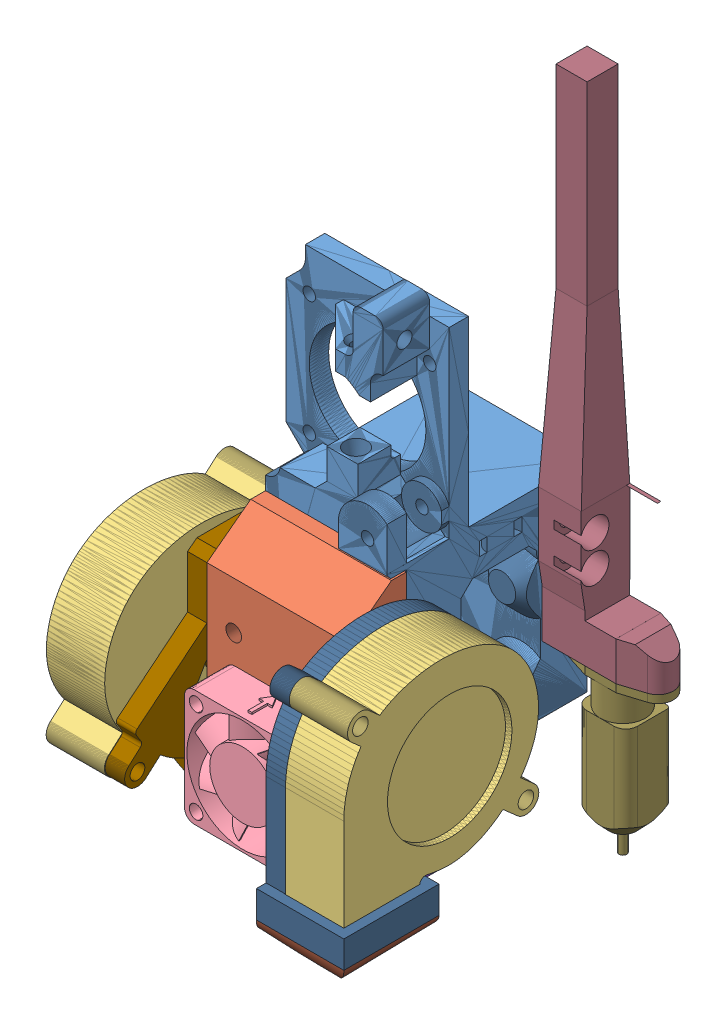
SolidWorks assembly Extrusor, configuration Predeterminado. Lengths in mm.
Overall size (87.36 190.4 95.75).
15 component instances, 13 part files, 34 mates.
Components (placement in the parent):
- mount_motor-1: mount_motor [Predeterminado] at origin size (42 104.07 51.5)
- mount_motor_b_featureworks-2: mount_motor_b_featureworks [Predeterminado] at (5.75 -10 32.6) size (36.25 60 29)
- BlowerFan50-1: BlowerFan50 [Predeterminado] at (-14.25 -3.2581 32.7961) x (0 0 1) z (-1 0 0) size (50.18 49.25 15)
- BlowerFan50-2: BlowerFan50 [Predeterminado] at (62 -3.2581 82.6073) x (0 0 -1) z (1 0 0) size (50.18 49.25 15)
- 30mm Fan-1: 30mm Fan [Predeterminado] at (25.4698 7.0502 72.1) x (1 0 0) z (0 0 -1) size (30 30.5 10.5)
- ED3V6-1: ED3V6 [Predeterminado] at (25.5254 -6.75 42.9799) x (-1 0 0) z (0 0 -1) size (26.65 63.25 22.3)
  - HEATSINK-1: HEATSINK [Predeterminado] at origin size (22.3 42.7 22.3)
  - NOZZLE 0.4-1: NOZZLE 0.4 [Predeterminado] at (0 -18.55 0) x (0.999537 0 -0.030412) z (0.030412 0 0.999537) size (8.08 12.5 7)
  - HEATBRICK-1: HEATBRICK [Predeterminado] at (0 -7.6 0) x (0.965851 0 -0.259098) z (0.259098 0 0.965851) size (7 21.9 7)
  - HEATERBLOCK-1: HEATERBLOCK [Predeterminado] at (-5.5 -15.1 0) size (20 11.5 16)
- FanAdapterWide-1: FanAdapterWide [Predeterminado] at (0.75 -3.2581 32.7961) x (0 0 -1) z (1 0 0) size (52.78 90.63 58.11)
- FanAdapterNarrow^Extrusor-1: FanAdapterNarrow^Extrusor [Predeterminado] at (42 -10 32.6) x (0 0 -1) z (1 0 0) size (63.31 92.39 40.57)
- FanAdapterNarrowTube-1: FanAdapterNarrowTube [Default] at origin size (42.1 18.18 31.65)
- BL-touch-1: BL-touch [Predeterminado] at (57 17.1 5.7838) x (-1 0 0) z (0 1 0) size (26 11.57 42.4)
- soporteBL-1: soporteBL [Predeterminado] at (42 -1.9435 -44.0657) x (0 0 -1) z (1 0 0) size (12.51 126.9 28)
Mates (geometry in assembly coordinates):
- Distancia1: distance = 0 mm: line of mount_motor-1 through (5.75 23 46.5) axis (0 1 0); line of mount_motor_b_featureworks-2 through (5.75 50 46.5) axis (0 -1 0)
- Distancia2: distance = 0 mm: line of mount_motor_b_featureworks-2 through (42 23 46.5) axis (0 0 -1); line of mount_motor-1 through (42 23 46.5) axis (0 0 -1)
- Coincidente3: coincident: point of mount_motor_b_featureworks-2; point of 30mm Fan-1
- Distancia4: distance = 0.2 mm anti-aligned: plane of ED3V6-1/HEATSINK-1 through (17.5254 35.95 42.9799) normal (0 1 0); plane of mount_motor-1 through (0 36.15 0) normal (0 -1 0)
- EnPosición1: in place: plane of ? through (-9.2109 -10.1962 32.7961) normal (0 -1 0); plane of ? through (0 -10.1962 0) normal (0 -1 0); moOrthogonalPlaneRef_w of ? through (-9.2109 -10.1962 32.7961) normal (0 -1 0); unknown of ?; plane of ? through (-9.2109 -10.1962 32.7961) normal (0 -1 0); line of ? through (-55 0 -10.1962) axis (0 -1 0); plane of ? through (-9.2109 -10.1962 32.7961) normal (0 -1 0); unknown of ?
- Coincidente13: coincident aligned: plane of BlowerFan50-1; plane of ?
- Coincidente14: coincident aligned: moOrthogonalPlaneRef_w of BlowerFan50-1 through (-9.2109 -10.1962 32.7961) normal (1 0 0); plane of ?
- Coincidente15: coincident anti-aligned: moOrthogonalPlaneRef_w of BlowerFan50-1 through (-9.2109 -10.1962 32.7961) normal (0 0 1); plane of ?
- EnPosición2: in place: plane of ? through (-9.2109 -10.1962 32.7961) normal (0 -1 0); plane of ? through (0 -10.1962 0) normal (0 -1 0); plane of ? through (-9.2109 -10.1962 32.7961) normal (0 -1 0); unknown of ?; plane of ? through (-9.2109 -10.1962 32.7961) normal (0 -1 0); line of ? through (-55 0 -10.1962) axis (0 -1 0); plane of ? through (-9.2109 -10.1962 32.7961) normal (0 -1 0); unknown of ?
- Coincidente16: coincident aligned: plane of BlowerFan50-1; plane of ?
- Coincidente17: coincident aligned: moOrthogonalPlaneRef_w of BlowerFan50-1 through (-9.2109 -10.1962 32.7961) normal (1 0 0); plane of ?
- Coincidente18: coincident anti-aligned: moOrthogonalPlaneRef_w of BlowerFan50-1 through (-9.2109 -10.1962 32.7961) normal (0 0 1); plane of ?
- EnPosición3: in place: plane of ? through (-9.2109 -10.1962 32.7961) normal (0 -1 0); plane of ? through (0 -10.1962 0) normal (0 -1 0); plane of ? through (-9.2109 -10.1962 32.7961) normal (0 -1 0); unknown of ?; plane of ? through (-9.2109 -10.1962 32.7961) normal (0 -1 0); line of ? through (-55 0 -10.1962) axis (0 -1 0); plane of ? through (-9.2109 -10.1962 32.7961) normal (0 -1 0); unknown of ?
- Coincidente19: coincident aligned: plane of BlowerFan50-1; plane of ?
- Coincidente20: coincident aligned: moOrthogonalPlaneRef_w of BlowerFan50-1 through (-9.2109 -10.1962 32.7961) normal (1 0 0); plane of ?
- Coincidente21: coincident anti-aligned: moOrthogonalPlaneRef_w of BlowerFan50-1 through (-9.2109 -10.1962 32.7961) normal (0 0 1); plane of ?
- Concéntrica1: concentric anti-aligned: circle of mount_motor-1; circle of ED3V6-1/HEATSINK-1
- EnPosición4: in place: plane of ? through (-44.2109 -10.1962 32.7961) normal (1 0 0); plane of ? through (-44.2109 0 0) normal (1 0 0); plane of ? through (-44.2109 -10.1962 32.7961) normal (1 0 0); line of ? through (-55 -44.2109 0) axis (0 0 1); plane of ? through (-44.2109 -10.1962 32.7961) normal (1 0 0); plane of ? through (-44.2109 0 0) normal (0 0 -1); plane of BlowerFan50-1 through (0.75 -3.2581 32.7961) normal (1 0 0); unknown of FanAdapterWide-1
- Coincidente23: coincident aligned: plane of BlowerFan50-1; plane of FanAdapterWide-1
- Coincidente24: coincident aligned: moOrthogonalPlaneRef_w of BlowerFan50-1 through (0.75 -3.2581 32.7961) normal (0 1 0); plane of FanAdapterWide-1 through (0.75 -3.2581 32.7961) normal (0 1 0)
- Coincidente25: coincident anti-aligned: moOrthogonalPlaneRef_w of BlowerFan50-1 through (0.75 -3.2581 32.7961) normal (0 0 1); plane of FanAdapterWide-1 through (0.75 -3.2581 32.7961) normal (0 0 -1)
- Coincidente26: coincident anti-aligned: plane of BlowerFan50-1 through (0.75 -3.2581 32.7961) normal (1 0 0); plane of FanAdapterWide-1 through (0.75 42.7286 41.9441) normal (-1 0 0)
- Coincidente27: coincident anti-aligned: plane of mount_motor_b_featureworks-2 through (5.75 -10 32.6) normal (-1 0 0); plane of FanAdapterWide-1 through (5.75 42.7286 41.9441) normal (1 0 0)
- Distancia6: distance = 0 mm aligned: plane of BlowerFan50-2 through (62 -3.2581 82.6073) normal (0 -1 0); plane of BlowerFan50-1 through (-14.25 -3.2581 32.7961) normal (0 -1 0)
- EnPosición5: in place: plane of mount_motor_b_featureworks-2 through (42 -10 32.6) normal (1 0 0); plane of ? through (42 0 0) normal (1 0 0); plane of mount_motor_b_featureworks-2 through (42 -10 32.6) normal (1 0 0); line of ? through (-55 42 0) axis (0 0 1); plane of mount_motor_b_featureworks-2 through (42 -10 32.6) normal (1 0 0); plane of ? through (42 0 0) normal (0 0 -1); plane of mount_motor_b_featureworks-2 through (42 -10 32.6) normal (1 0 0); unknown of FanAdapterNarrow^Extrusor-1
- Coincidente28: coincident aligned: plane of mount_motor_b_featureworks-2; plane of FanAdapterNarrow^Extrusor-1
- Coincidente29: coincident aligned: moOrthogonalPlaneRef_w of mount_motor_b_featureworks-2 through (42 -10 32.6) normal (0 1 0); plane of FanAdapterNarrow^Extrusor-1 through (42 -10 32.6) normal (0 1 0)
- Coincidente30: coincident anti-aligned: moOrthogonalPlaneRef_w of mount_motor_b_featureworks-2 through (42 -10 32.6) normal (0 0 1); plane of FanAdapterNarrow^Extrusor-1 through (42 -10 32.6) normal (0 0 -1)
- Coincidente28: coincident anti-aligned: plane of BlowerFan50-2 through (47 -3.2581 82.6073) normal (-1 0 0); plane of FanAdapterNarrow^Extrusor-1 through (47 -10 32.6) normal (1 0 0)
- Distancia8: distance = 2 mm aligned: plane of BL-touch-1 through (57 -25.3 5.7838) normal (0 -1 0); plane of assembly through (0 -27.3 0) normal (0 -1 0)
- Coincidente29: coincident: plane of mount_motor-1 through (42 0 0) normal (1 0 0); point of soporteBL-1
- Paralelo1: parallel aligned: plane of BL-touch-1 through (57 -25.3 5.7838) normal (0 -1 0); plane of assembly through (0 -27.3 0) normal (0 -1 0)
- Distancia9: distance = 0 mm aligned: plane of BL-touch-1 through (62.5268 -18.9 0) normal (0 0 -1); plane of mount_motor-1 through (0 0 0) normal (0 0 -1)
- Distancia10: distance = 2 mm anti-aligned: cylinder of BL-touch-1 through (48.002 15.1 5.7844) axis (0 1 0) radius 4.002; plane of mount_motor-1 through (42 0 0) normal (1 0 0)
